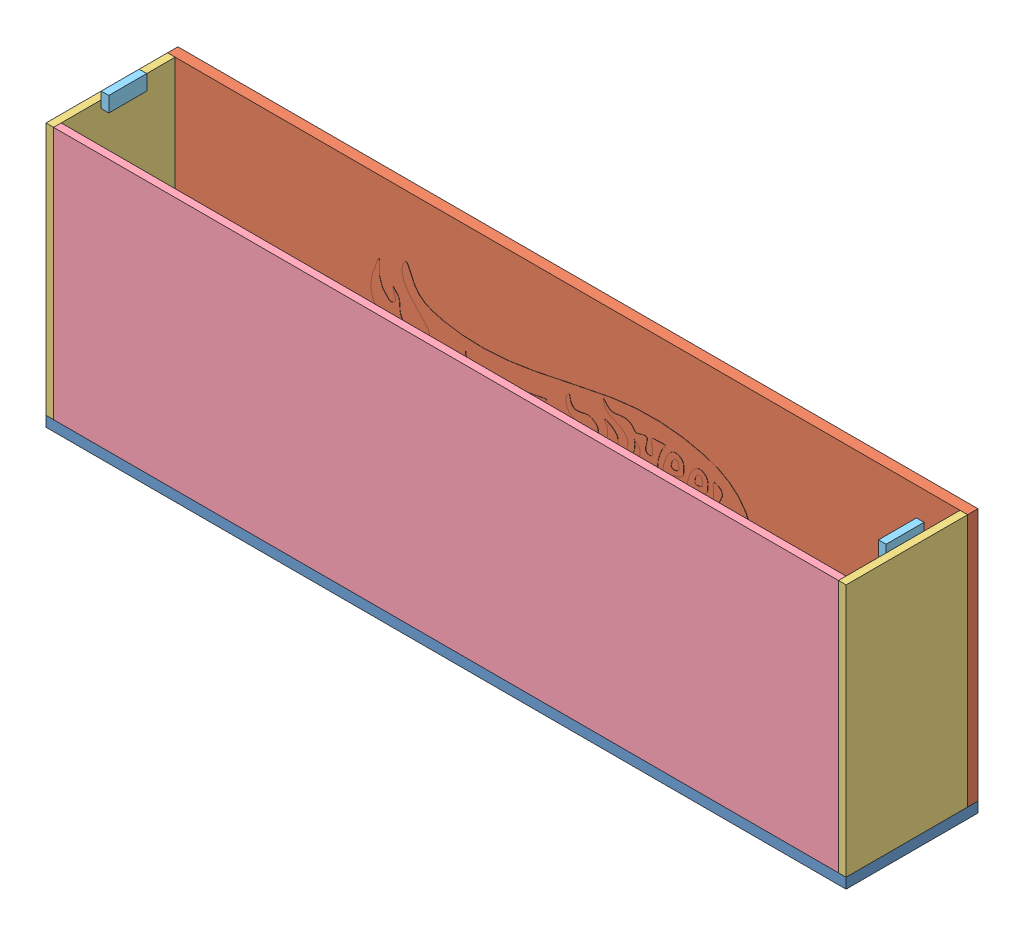
SolidWorks assembly omhulsel grot en afschiet, configuration Default. Lengths in mm.
Overall size (316 107.1 52.1).
7 component instances, 5 part files, 18 mates.
Components (placement in the parent):
- onderstuk grot en afschiet-2: onderstuk grot en afschiet [Default] at (30.6252 101.7482 299.0234) size (316 4.3 52.1)
- achterkant grot en afschiet-2: achterkant grot en afschiet [Default] at (30.6252 151.7482 277.0734) x (1 0 0) z (0 -1 0) size (316 4.3 100)
- doorzichtig zijkant grot en afschiet-1: doorzichtig zijkant grot en afschiet [Default] at (-124.3748 151.7482 301.0734) x (0 0 1) z (0 -1 0) size (48 3 100)
- doorzichtig zijkant grot en afschiet-2: doorzichtig zijkant grot en afschiet [Default] at (188.6252 151.7482 301.0734) x (0 0 1) z (0 -1 0) size (48 3 100)
- doorzichtig voorkant grot en afschiet-1: doorzichtig voorkant grot en afschiet [Default] at (30.6252 151.7482 322.0734) x (1 0 0) z (0 -1 0) size (310 3 100)
- plaatje 6 x15 x 3 grot en afschiet-1: plaatje 6 x15 x 3 grot en afschiet [Default] at (-121.3748 201.7482 298.7734) x (0 1 0) z (0 0 1) size (6 3 15)
- plaatje 6 x15 x 3 grot en afschiet-2: plaatje 6 x15 x 3 grot en afschiet [Default] at (182.6252 201.7482 298.7734) x (0 -1 0) z (0 0 1) size (6 3 15)
Mates (geometry in assembly coordinates):
- Coincident1: coincident: plane of onderstuk grot en afschiet-2 through (30.6252 101.7482 299.0234) normal (0 1 0); plane of achterkant grot en afschiet-2 through (188.6252 101.7482 272.9734) normal (0 -1 0)
- Coincident2: coincident: plane of onderstuk grot en afschiet-2 through (188.6252 97.6482 325.0734) normal (1 0 0); plane of achterkant grot en afschiet-2 through (188.6252 101.7482 272.9734) normal (1 0 0)
- Coincident3: coincident: plane of onderstuk grot en afschiet-2 through (188.6252 97.6482 272.9734) normal (0 0 -1); plane of achterkant grot en afschiet-2 through (30.6252 151.7482 272.9734) normal (0 0 -1)
- Coincident4: coincident: plane of onderstuk grot en afschiet-2 through (30.6252 101.7482 299.0234) normal (0 1 0); plane of doorzichtig zijkant grot en afschiet-1 through (-127.3748 101.7482 325.0734) normal (0 -1 0)
- Coincident5: coincident: plane of onderstuk grot en afschiet-2 through (-127.3748 97.6482 325.0734) normal (-1 0 0); plane of doorzichtig zijkant grot en afschiet-1 through (-127.3748 151.7482 301.0734) normal (-1 0 0)
- Coincident6: coincident: plane of onderstuk grot en afschiet-2 through (188.6252 97.6482 325.0734) normal (0 0 1); plane of doorzichtig zijkant grot en afschiet-1 through (-127.3748 101.7482 325.0734) normal (0 0 1)
- Coincident7: coincident: plane of onderstuk grot en afschiet-2 through (30.6252 101.7482 299.0234) normal (0 1 0); plane of doorzichtig zijkant grot en afschiet-2 through (185.6252 101.7482 325.0734) normal (0 -1 0)
- Coincident8: coincident: plane of onderstuk grot en afschiet-2 through (188.6252 97.6482 325.0734) normal (0 0 1); plane of doorzichtig zijkant grot en afschiet-2 through (185.6252 101.7482 325.0734) normal (0 0 1)
- Coincident9: coincident: plane of onderstuk grot en afschiet-2 through (188.6252 97.6482 325.0734) normal (1 0 0); plane of doorzichtig zijkant grot en afschiet-2 through (188.6252 151.7482 301.0734) normal (1 0 0)
- Coincident10: coincident: plane of onderstuk grot en afschiet-2 through (30.6252 101.7482 299.0234) normal (0 1 0); plane of doorzichtig voorkant grot en afschiet-1 through (185.6252 101.7482 325.0734) normal (0 -1 0)
- Coincident11: coincident: plane of onderstuk grot en afschiet-2 through (188.6252 97.6482 325.0734) normal (0 0 1); plane of doorzichtig voorkant grot en afschiet-1 through (30.6252 151.7482 325.0734) normal (0 0 1)
- Coincident12: coincident: plane of doorzichtig zijkant grot en afschiet-2 through (185.6252 151.7482 301.0734) normal (-1 0 0); plane of doorzichtig voorkant grot en afschiet-1 through (185.6252 101.7482 325.0734) normal (1 0 0)
- Coincident13: coincident: plane of doorzichtig zijkant grot en afschiet-1 through (-124.3748 151.7482 301.0734) normal (1 0 0); plane of plaatje 6 x15 x 3 grot en afschiet-1 through (-124.3748 201.7482 298.7734) normal (-1 0 0)
- Distance1: distance = 3 mm: plane of plaatje 6 x15 x 3 grot en afschiet-1 through (-124.3748 204.7482 306.2734) normal (0 1 0); plane of doorzichtig zijkant grot en afschiet-1 through (-127.3748 201.7482 325.0734) normal (0 1 0)
- Distance2: distance = 18.3 mm: plane of plaatje 6 x15 x 3 grot en afschiet-1 through (-124.3748 204.7482 291.2734) normal (0 0 -1); plane of achterkant grot en afschiet-2 through (30.6252 151.7482 272.9734) normal (0 0 -1)
- Coincident17: coincident: plane of doorzichtig zijkant grot en afschiet-2 through (185.6252 151.7482 301.0734) normal (-1 0 0); plane of plaatje 6 x15 x 3 grot en afschiet-2 through (185.6252 201.7482 298.7734) normal (1 0 0)
- Distance3: distance = 3 mm: plane of plaatje 6 x15 x 3 grot en afschiet-2 through (185.6252 204.7482 306.2734) normal (0 1 0); plane of doorzichtig zijkant grot en afschiet-2 through (185.6252 201.7482 325.0734) normal (0 1 0)
- Distance4: distance = 18.3 mm: plane of plaatje 6 x15 x 3 grot en afschiet-2 through (185.6252 198.7482 291.2734) normal (0 0 -1); plane of achterkant grot en afschiet-2 through (30.6252 151.7482 272.9734) normal (0 0 -1)
